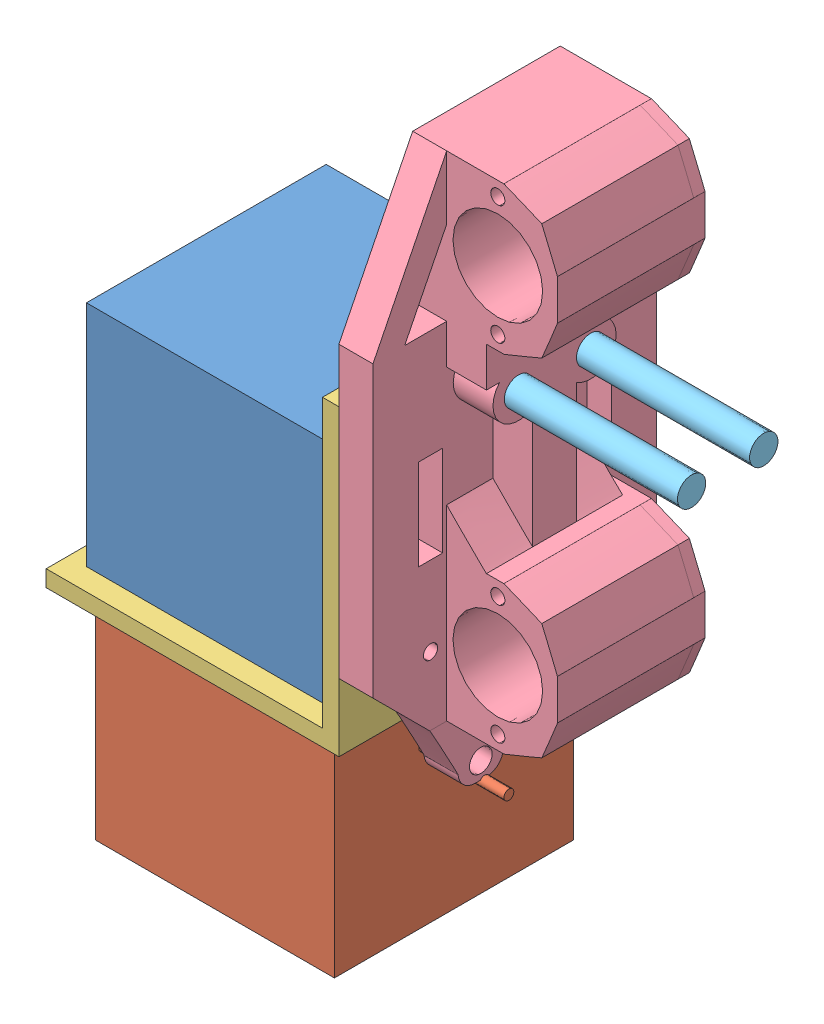
SolidWorks assembly extruderAssem, configuration Default. Lengths in mm.
Overall size (100.34 127.1 50).
6 component instances, 5 part files, 14 mates.
Components (placement in the parent):
- extruder-2: extruder [Default] at (8.538 -7.5283 -13.6971) size (42.24 40.25 42.24)
- extruderNonMotorPart-2: extruderNonMotorPart [Default] at (10.058 -10.4283 -13.7671) x (0 0 -1) z (-1 0 0) size (42.1 38.1 67.1)
- motorMount-1: motorMount [Default] at (5.318 -10.4283 -9.8271) size (51.58 53.4 49.98)
- extruderHolder-1: extruderHolder [Default] at (62.898 52.5217 -22.8171) x (0 1 0) z (0 0 -1) size (99.05 25.62 50)
- bolt-1: bolt [Default] at (56.898 42.5217 -28.4621) x (0 0.381849 -0.924225) z (0 -0.924225 -0.381849) size (7.5 43.5 7.5)
- bolt-2: bolt [Default] at (56.898 42.5217 -41.1721) x (0 0.381849 -0.924225) z (0 -0.924225 -0.381849) size (7.5 43.5 7.5)
Mates (geometry in assembly coordinates):
- Coincident1: coincident anti-aligned: plane of extruder-2 through (8.538 -7.5283 -13.6971) normal (0 -1 0); plane of motorMount-1 through (5.318 -7.5283 -9.8271) normal (0 1 0)
- Width1: width aligned: plane of extruder-2 through (8.538 32.7217 -13.6971) normal (0 0 1); plane of motorMount-1 through (8.538 32.7217 -55.9371) normal (0 0 -1); plane of extruder-2 through (5.318 -7.5283 -9.8271) normal (0 0 1); plane of motorMount-1 through (5.318 -7.5283 -59.8071) normal (0 0 -1)
- Width2: width aligned: plane of extruder-2 through (8.538 32.7217 -13.6971) normal (-1 0 0); plane of motorMount-1 through (50.778 32.7217 -13.6971) normal (1 0 0); plane of extruder-2 through (53.998 42.9717 -9.8271) normal (-1 0 0); plane of motorMount-1 through (5.318 -7.5283 -9.8271) normal (-1 0 0)
- Coincident3: coincident anti-aligned: plane of extruderNonMotorPart-2 through (10.058 -10.4283 -13.7671) normal (0 1 0); plane of motorMount-1 through (5.318 -10.4283 -9.8271) normal (0 -1 0)
- Parallel1: parallel aligned: plane of extruderNonMotorPart-2 through (10.058 -48.5283 -13.7671) normal (-1 0 0); plane of motorMount-1 through (5.318 -7.5283 -9.8271) normal (-1 0 0)
- Width7: width anti-aligned: plane of extruderNonMotorPart-2 through (10.058 -48.5283 -13.7671) normal (0 0 1); plane of motorMount-1 through (10.058 -48.5283 -55.8671) normal (0 0 -1); plane of extruderNonMotorPart-2 through (5.318 -7.5283 -59.8071) normal (0 0 -1); plane of motorMount-1 through (5.318 -7.5283 -9.8271) normal (0 0 1)
- Width8: width anti-aligned: plane of extruderNonMotorPart-2 through (52.158 -48.5283 -13.7671) normal (1 0 0); plane of motorMount-1 through (10.058 -48.5283 -13.7671) normal (-1 0 0); plane of extruderNonMotorPart-2 through (5.318 -7.5283 -9.8271) normal (-1 0 0); plane of motorMount-1 through (56.898 -7.5283 -9.8271) normal (1 0 0)
- Concentric1: concentric aligned: cylinder of extruderHolder-1 through (82.448 42.5217 -41.1721) axis (-1 0 0) radius 2.5; cylinder of bolt-2 through (100.398 42.5217 -41.1721) axis (-1 0 0) radius 2.5
- Concentric2: concentric aligned: cylinder of extruderHolder-1 through (82.448 42.5217 -28.4621) axis (-1 0 0) radius 2.5; cylinder of bolt-1 through (100.398 42.5217 -28.4621) axis (-1 0 0) radius 2.5
- Coincident7: coincident anti-aligned: plane of extruderHolder-1 through (60.398 42.5217 -41.1721) normal (-1 0 0); plane of bolt-2 through (60.398 42.5217 -41.1721) normal (1 0 0)
- Coincident8: coincident anti-aligned: plane of extruderHolder-1 through (60.398 42.5217 -28.4621) normal (-1 0 0); plane of bolt-1 through (60.398 42.5217 -28.4621) normal (1 0 0)
- Coincident9: coincident anti-aligned: plane of motorMount-1 through (56.898 -7.5283 -9.8271) normal (1 0 0); plane of extruderHolder-1 through (56.898 -8.4783 -46.8171) normal (-1 0 0)
- Coincident10: coincident aligned: plane of motorMount-1 through (5.318 33.5217 -47.5271) normal (0 -1 0); plane of extruderHolder-1 through (40.3354 33.5217 -22.8171) normal (0 -1 0)
- Coincident11: coincident aligned: plane of motorMount-1 through (5.318 33.5217 -47.5271) normal (0 0 -1); plane of extruderHolder-1 through (40.3354 52.5217 -47.5271) normal (0 0 -1)
